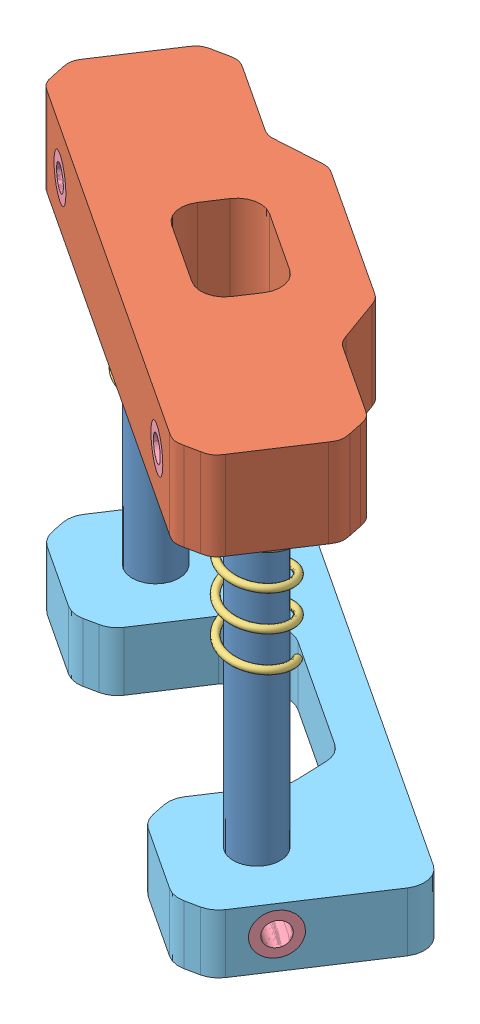
SolidWorks assembly Systeme Encodeurs Partie Fixe, configuration Défaut. Lengths in mm.
Overall size (87.84 77.05 72.95).
12 component instances, 5 part files, 54 mates.
Components (placement in the parent):
- Axe_Support_Codeurs-1: Axe_Support_Codeurs [Défaut] at (-9.7273 -8.3238 48.8402) size (8 72 8)
- Support Ressort-1: Support Ressort [Défaut] at (15.3415 51.6762 65.3192) x (0.835626 0 0.549299) z (-0.549299 0 0.835626) size (84.1 15.1 30.1)
- Axe_Support_Codeurs-2: Axe_Support_Codeurs [Défaut] at (40.4103 -8.3238 81.7982) x (-0.166467 0 0.986047) z (-0.986047 0 -0.166467) size (8 72 8)
- Ressort M8-1: Ressort M8 [Défaut] at (40.4103 28.0864 81.7982) x (-0.557817 0 -0.829964) z (0.829964 0 -0.557817) size (12.72 24.18 12.45)
- Ressort M8-2: Ressort M8 [Défaut] at (-9.7273 28.0864 48.8402) x (0.981205 0 0.19297) z (-0.19297 0 0.981205) size (12.72 24.18 12.45)
- Insert M4-1: Insert M4 [Défaut] at (-15.2744 59.1762 59.5544) x (0.385453 0.887257 0.253378) z (0.549299 0 -0.835626) size (7 7 8)
- Insert M4-4: Insert M4 [Défaut] at (32.7741 59.1762 91.1391) x (0.376232 0.892908 0.247316) z (0.549299 0 -0.835626) size (7 7 8)
- Support Plaque Encodeurs-1: Support Plaque Encodeurs [Défaut] at (15.3415 -10.3238 65.3192) x (0.835626 0 0.549299) z (-0.549299 0 0.835626) size (84 10 32)
- Insert M4-5: Insert M4 [Défaut] at (50.4378 -4.8238 88.3898) x (-0.376825 -0.727591 0.573249) z (-0.835626 0 -0.549299) size (7 7 8)
- Insert M4-6: Insert M4 [Défaut] at (-19.7548 -4.8238 42.2487) x (-0.505419 -0.391644 0.768874) z (0.835626 0 0.549299) size (7 7 8)
- Insert M4-7: Insert M4 [Défaut] at (51.7293 -10.3238 73.6815) x (0.445123 0 0.895469) z (0 1 0) size (7 7 8)
- Insert M4-8: Insert M4 [Défaut] at (-6.7646 -10.3238 35.2306) x (0.956517 0 -0.291677) z (0 1 0) size (7 7 8)
Mates (geometry in assembly coordinates):
- Coaxiale1: concentric anti-aligned: cylinder of Axe_Support_Codeurs-1 through (-9.7273 63.6762 48.8402) axis (0 -1 0) radius 4; cylinder of ? through (-9.7273 2.4164 48.8402) axis (0 1 0) radius 4
- Coaxiale4: concentric anti-aligned: cylinder of Axe_Support_Codeurs-2 through (40.4103 63.6762 81.7982) axis (0 -1 0) radius 4; cylinder of ? through (42.7043 2.4164 78.011) axis (0 1 0) radius 4
- Coaxiale8: concentric: cylinder of ? through (-9.7273 25.6164 48.8402) axis (0 1 0) radius 4; cylinder of Axe_Support_Codeurs-1 through (-9.7273 63.6762 48.8402) axis (0 -1 0) radius 4
- Coaxiale9: concentric anti-aligned: cylinder of Axe_Support_Codeurs-2 through (40.4103 63.6762 81.7982) axis (0 -1 0) radius 4; cylinder of ? through (42.7043 25.6164 78.011) axis (0 1 0) radius 4
- Coïncidente3: coincident: plane of ? through (42.7043 26.4164 78.011) normal (0 1 0); plane of ? through (42.7043 26.4164 78.011) normal (0 -1 0)
- Coïncidente4: coincident: plane of ? through (-9.7273 26.4164 48.8402) normal (0 1 0); plane of ? through (-9.7273 26.4164 48.8402) normal (0 -1 0)
- Coïncidente5: coincident: plane of ? through (16.4885 26.4164 63.4256) normal (0 1 0); plane of ? through (-9.7273 26.4164 48.8402) normal (0 -1 0)
- Coïncidente6: coincident: plane of ? through (16.4885 26.4164 63.4256) normal (0 1 0); plane of ? through (42.7043 26.4164 78.011) normal (0 -1 0)
- Coaxiale10: concentric: cylinder of ? through (17.1967 11.4762 30.977) axis (-0.822784 0 -0.568354) radius 1.8; cylinder of ? through (12.6714 11.4762 27.851) axis (0.822784 0 0.568354) radius 1.8
- Coaxiale11: concentric: cylinder of ? through (21.6266 24.9762 24.564) axis (-0.822784 0 -0.568354) radius 1.8; cylinder of ? through (17.1013 24.9762 21.4381) axis (0.822784 0 0.568354) radius 1.8
- Coaxiale12: concentric: cylinder of ? through (12.7668 24.9762 37.3899) axis (-0.822784 0 -0.568354) radius 1.8; cylinder of ? through (8.2415 24.9762 34.264) axis (0.822784 0 0.568354) radius 1.8
- Coïncidente7: coincident: plane of ? through (15.1398 20.4762 29.5561) normal (-0.822784 0 -0.568354); plane of ? through (15.1398 20.4762 29.5561) normal (0.822784 0 0.568354)
- Coaxiale14: concentric: cylinder of ? through (21.6266 24.9762 24.564) axis (-0.822784 0 -0.568354) radius 1.8; cylinder of ? through (17.5127 24.9762 21.7222) axis (0.822784 0 0.568354) radius 1.8
- Coaxiale15: concentric: cylinder of ? through (12.7668 24.9762 37.3899) axis (-0.822784 0 -0.568354) radius 1.8; cylinder of ? through (8.6529 24.9762 34.5482) axis (0.822784 0 0.568354) radius 1.8
- Coaxiale16: concentric: cylinder of ? through (17.1967 11.4762 30.977) axis (-0.822784 0 -0.568354) radius 1.8; cylinder of ? through (13.0828 11.4762 28.1352) axis (0.822784 0 0.568354) radius 1.8
- Coïncidente8: coincident: plane of ?; plane of ? through (12.7668 24.9762 37.3899) normal (-0.822784 0 -0.568354)
- Coïncidente9: coincident: plane of ?; plane of ? through (21.6266 24.9762 24.564) normal (-0.822784 0 -0.568354)
- Coïncidente10: coincident: plane of ?; plane of ? through (17.1967 11.4762 30.977) normal (-0.822784 0 -0.568354)
- Coaxiale19: concentric anti-aligned: cylinder of Axe_Support_Codeurs-2 through (40.4103 63.6762 81.7982) axis (0 -1 0) radius 4; circle of Ressort M8-1
- Coaxiale20: concentric anti-aligned: cylinder of Axe_Support_Codeurs-1 through (-9.7273 63.6762 48.8402) axis (0 -1 0) radius 4; circle of Ressort M8-2
- Coïncidente11: coincident anti-aligned: plane of Axe_Support_Codeurs-1 through (-9.7273 63.6762 48.8402) normal (0 1 0); plane of Support Ressort-1 through (15.3415 63.6762 65.3192) normal (0 -1 0)
- Coaxiale21: concentric aligned: cylinder of Axe_Support_Codeurs-1 through (-9.7273 63.6762 48.8402) axis (0 -1 0) radius 4; cylinder of Support Ressort-1 through (-9.7273 63.6762 48.8402) axis (0 -1 0) radius 4
- Coïncidente14: coincident anti-aligned: plane of Support Ressort-1 through (15.3415 63.6762 65.3192) normal (0 -1 0); plane of Axe_Support_Codeurs-2 through (40.4103 63.6762 81.7982) normal (0 1 0)
- Coïncidente13: coincident aligned: plane of Support Ressort-1 through (8.7499 66.6762 75.3467) normal (-0.549299 0 0.835626); plane of Insert M4-1 through (-15.2744 59.1762 59.5544) normal (-0.549299 0 0.835626)
- Coaxiale24: concentric anti-aligned: cylinder of Support Ressort-1 through (32.7467 59.1762 91.1808) axis (0.549299 0 -0.835626) radius 2.75; cylinder of ? through (43.1676 57.1762 81.3008) axis (-0.769806 0 0.638278) radius 2.75
- Coaxiale26: concentric anti-aligned: cylinder of Support Ressort-1 through (-15.3018 59.1762 59.5962) axis (0.549299 0 -0.835626) radius 2.75; cylinder of ? through (6.4667 57.1762 37.0369) axis (-0.769806 0 0.638278) radius 2.75
- Coïncidente16: coincident anti-aligned: plane of Support Ressort-1 through (21.9331 66.6762 55.2917) normal (0.549299 0 -0.835626); plane of ? through (0.3082 57.1762 42.1432) normal (-0.769806 0 0.638278)
- Coïncidente17: coincident aligned: plane of Support Ressort-1 through (8.7499 66.6762 75.3467) normal (-0.549299 0 0.835626); plane of Insert M4-4 through (32.7741 59.1762 91.1391) normal (-0.549299 0 0.835626)
- Coaxiale28: concentric: cylinder of ? through (18.0195 20.4762 31.5453) axis (-0.822784 0 -0.568354) radius 2.5; cylinder of ? through (29.1271 20.4762 39.2181) axis (-0.822784 0 -0.568354) radius 2.1
- Coïncidente18: coincident: plane of ? through (15.1398 20.4762 29.5561) normal (0.822784 0 0.568354); plane of ?
- Coaxiale29: concentric: cylinder of ? through (10.63 -8.0836 73.9556) axis (0.486179 0 -0.873859) radius 1.8; cylinder of ? through (13.5714 -8.0836 68.6688) axis (-0.486179 0 0.873859) radius 1.8
- Coaxiale30: concentric: cylinder of ? through (3.819 5.4164 70.1662) axis (0.486179 0 -0.873859) radius 1.8; cylinder of ? through (6.7603 5.4164 64.8794) axis (-0.486179 0 0.873859) radius 1.8
- Coïncidente19: coincident: plane of ? through (12.1129 2.4164 71.2903) normal (0.486179 0 -0.873859); plane of ? through (12.1129 0.9164 71.2903) normal (-0.486179 0 0.873859)
- Coaxiale31: concentric: cylinder of ? through (-32.905 9.6159 81.0706) axis (0.995895 0 -0.090519) radius 2.1; cylinder of ? through (-19.4604 9.6159 79.8486) axis (0.995895 0 -0.090519) radius 2.5
- Coïncidente20: coincident: plane of ? through (-15.9748 9.6159 79.5318) normal (0.995895 0 -0.090519); plane of ?
- Coaxiale32: concentric aligned: cylinder of Axe_Support_Codeurs-1 through (-9.7273 63.6762 48.8402) axis (0 -1 0) radius 4; cylinder of Support Plaque Encodeurs-1 through (-9.7273 -0.3238 48.8402) axis (0 -1 0) radius 4
- Coaxiale33: concentric aligned: cylinder of Axe_Support_Codeurs-2 through (40.4103 63.6762 81.7982) axis (0 -1 0) radius 4; cylinder of Support Plaque Encodeurs-1 through (40.4103 -0.3238 81.7982) axis (0 -1 0) radius 4
- Coïncidente21: coincident anti-aligned: plane of Axe_Support_Codeurs-1 through (-9.7273 -8.3238 48.8402) normal (0 -1 0); plane of Support Plaque Encodeurs-1 through (-9.7273 -8.3238 48.8402) normal (0 1 0)
- Coaxiale34: concentric aligned: cylinder of Support Plaque Encodeurs-1 through (50.4386 -4.8238 88.3903) axis (-0.835626 0 -0.549299) radius 2.75; cylinder of Insert M4-6 through (-13.0698 -4.8238 46.643) axis (-0.835626 0 -0.549299) radius 2.75
- Coïncidente22: coincident aligned: plane of Support Plaque Encodeurs-1 through (-19.7548 -0.3238 42.2487) normal (-0.835626 0 -0.549299); plane of Insert M4-6 through (-19.7548 -4.8238 42.2487) normal (-0.835626 0 -0.549299)
- Coaxiale35: concentric aligned: cylinder of Support Plaque Encodeurs-1 through (-19.7557 -4.8238 42.2481) axis (0.835626 0 0.549299) radius 2.75; cylinder of Insert M4-5 through (43.7528 -4.8238 83.9954) axis (0.835626 0 0.549299) radius 2.75
- Coïncidente23: coincident aligned: plane of Support Plaque Encodeurs-1 through (50.4378 -0.3238 88.3898) normal (0.835626 0 0.549299); plane of Insert M4-5 through (50.4378 -4.8238 88.3898) normal (0.835626 0 0.549299)
- Coïncidente24: coincident anti-aligned: plane of Support Ressort-1 through (21.9331 66.6762 55.2917) normal (0.549299 0 -0.835626); plane of ? through (37.0092 57.1762 86.407) normal (-0.769806 0 0.638278)
- Coaxiale36: concentric aligned: cylinder of Support Ressort-1 through (40.4103 63.6762 81.7982) axis (0 -1 0) radius 4; cylinder of Axe_Support_Codeurs-2 through (40.4103 63.6762 81.7982) axis (0 -1 0) radius 4
- Coaxiale37: concentric aligned: cylinder of Support Plaque Encodeurs-1 through (-6.7646 -1.8238 35.2306) axis (0 -1 0) radius 2.75; cylinder of Insert M4-8 through (-6.7646 -2.3238 35.2306) axis (0 -1 0) radius 2.75
- Coaxiale38: concentric aligned: cylinder of Support Plaque Encodeurs-1 through (51.7293 -1.8238 73.6815) axis (0 -1 0) radius 2.75; cylinder of Insert M4-7 through (51.7293 -2.3238 73.6815) axis (0 -1 0) radius 2.75
- Coaxiale40: concentric: cylinder of ? through (-9.7273 2.4164 48.8402) axis (0 1 0) radius 7.5; cylinder of ? through (-9.7273 2.4164 48.8402) axis (0 1 0) radius 7.65
- Coaxiale41: concentric: cylinder of ? through (42.7043 2.4164 78.011) axis (0 1 0) radius 7.5; cylinder of ? through (42.7043 2.4164 78.011) axis (0 1 0) radius 7.7
- Coïncidente28: coincident anti-aligned: plane of Support Plaque Encodeurs-1 through (15.3415 -9.3238 65.3192) normal (0 -1 0); plane of Insert M4-8 through (-6.7646 -9.3238 35.2306) normal (0 1 0)
- Coïncidente29: coincident anti-aligned: plane of Support Plaque Encodeurs-1 through (15.3415 -9.3238 65.3192) normal (0 -1 0); plane of Insert M4-7 through (51.7293 -9.3238 73.6815) normal (0 1 0)
- Tangent9: tangent: plane of Support Ressort-1 through (15.3415 51.6762 65.3192) normal (0 -1 0); circle of Ressort M8-2
- Tangent10: tangent: plane of Support Ressort-1 through (15.3415 51.6762 65.3192) normal (0 -1 0); circle of Ressort M8-1
- Coaxiale42: concentric anti-aligned: cylinder of Support Ressort-1 through (32.7467 59.1762 91.1808) axis (0.549299 0 -0.835626) radius 2.75; cylinder of Insert M4-4 through (37.1685 59.1762 84.4541) axis (-0.549299 0 0.835626) radius 2.75
- Coaxiale43: concentric anti-aligned: cylinder of Support Ressort-1 through (-15.3018 59.1762 59.5962) axis (0.549299 0 -0.835626) radius 2.75; cylinder of Insert M4-1 through (-10.88 59.1762 52.8694) axis (-0.549299 0 0.835626) radius 2.75
